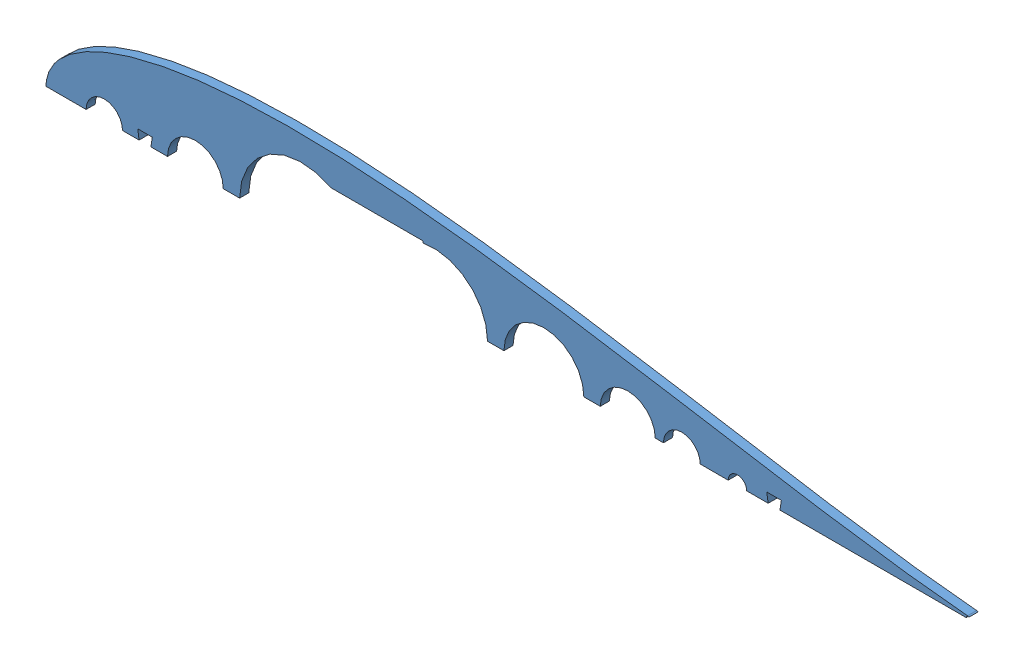
SolidWorks assembly Full Scale. Assembly Airfoil Servo Access, configuration Default. Lengths in mm.
Overall size (643.44 60.39 6.35).
2 component instances, 2 part files, 3 mates.
Components (placement in the parent):
- Prototype rib mk 4 female-1: Prototype rib mk 4 female [Default] at (-578.6111 14.9076 101.6027) size (643.6 60.39 6.35)
- Foam front wing base-1: Foam front wing base [Default] at (-578.6111 14.9076 -2330.4473) (suppressed, hidden)
Mates (geometry in assembly coordinates):
- Coincident7: coincident aligned: plane of Prototype rib mk 4 female-1 through (-578.6111 14.9076 107.9527) normal (0 0 1); plane of Foam front wing base-1 through (-578.6111 14.9076 107.9527) normal (0 0 1)
- Concentric1: concentric aligned: circle of Prototype rib mk 4 female-1; circle of Foam front wing base-1
- Coincident9: coincident aligned: line of Prototype rib mk 4 female-1 through (-578.6111 14.9076 107.9527) axis (1 0 0); line of Prototype rib mk 4 female-1 through (-578.6111 14.9076 107.9527) axis (1 0 0)
